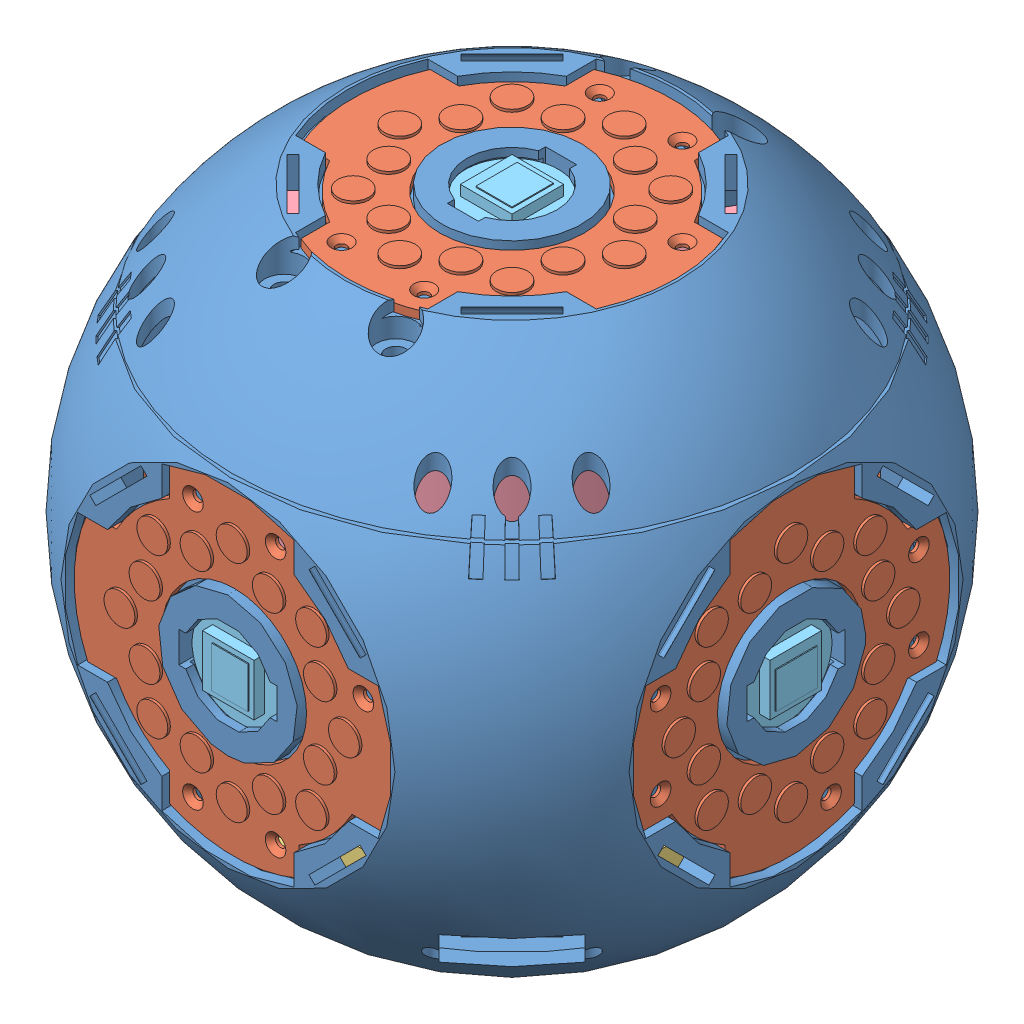
SolidWorks assembly Structural Module, configuration Passive Cube. Lengths in mm.
Overall size (63.8 63.8 63.8).
16 component instances, 5 part files, 41 mates.
Components (placement in the parent):
- Cube Shell-1: Cube Shell [Shell for Passive Cube (Large Part)] at origin size (63.8 63.8 63.8)
- Cube Shell-2: Cube Shell [Shell (Small Part)] at (0 -0.0475 0) size (55 59.4 55)
- Face Boards v2-1: Face Boards v2 [Default] at (0 0 26.1) x (1 0 0) z (0 -1 0) size (31 1.04 31)
- Face Boards v2-2: Face Boards v2 [Default] at (26.1 0 0) x (0 -1 0) z (0 0 1) size (31 1.04 31)
- Face Boards v2-3: Face Boards v2 [Default] at (0 0 -26.1) x (1 0 0) z (0 1 0) size (31 1.04 31)
- Face Boards v2-4: Face Boards v2 [Default] at (-26.1 0 0) x (0 1 0) z (0 0 1) size (31 1.04 31)
- Face Boards v2-5: Face Boards v2 [Default] at (0 -26.1 0) x (-1 0 0) z (0 0 1) size (31 1.04 31)
- Face Boards v2-6: Face Boards v2 [Default] at (0 26.0525 0) size (31 1.04 31)
- Controller PCB-1: Controller PCB [Default] at (0 -20.2874 0) x (-1 0 0) z (0 0 -1) size (43.18 6.79 43.18)
- Structural Module Internals-1: Structural Module Internals [ElectricImp] at (0 -6.4375 0) x (0 0 1) z (-1 0 0) size (49 29.1 49)
- AdjacencySensor-1: AdjacencySensor [Default] at (0 -24.9 0) x (-0.837169 0 -0.546944) z (-0.546944 0 0.837169) size (9 2.67 9)
- AdjacencySensor-2: AdjacencySensor [Default] at (24.9 0 0) x (0 -1 0) z (0 0 1) size (9 2.67 9)
- AdjacencySensor-3: AdjacencySensor [Default] at (0 0 -24.9) x (1 0 0) z (0 1 0) size (9 2.67 9)
- AdjacencySensor-4: AdjacencySensor [Default] at (0 0 24.9) x (1 0 0) z (0 -1 0) size (9 2.67 9)
- AdjacencySensor-5: AdjacencySensor [Default] at (0 24.8525 0) size (9 2.67 9)
- AdjacencySensor-6: AdjacencySensor [Default] at (-24.9 0 0) x (0 1 0) z (0 0 1) size (9 2.67 9)
Mates (geometry in assembly coordinates):
- Concentric1: concentric aligned: cylinder of Cube Shell-2 through (0 25.3525 0) axis (0 -1 0) radius 6.75; cylinder of Face Boards v2-6 through (0 26.8399 0) axis (0 -1 0) radius 7
- Coincident1: coincident anti-aligned: plane of Cube Shell-2 through (0 26.0525 0) normal (0 1 0); plane of Face Boards v2-6 through (0 26.0525 0) normal (0 -1 0)
- Parallel1: parallel aligned: line of Cube Shell-2 through (-6.4 27.4525 11.6589) axis (0 0 1); line of Face Boards v2-6 through (-6.25 26.8399 11.399) axis (0 0 1)
- Concentric2: concentric aligned: cylinder of Cube Shell-1 through (0 0 25.4) axis (0 0 -1) radius 6.75; cylinder of Face Boards v2-1 through (0 0 26.8874) axis (0 0 -1) radius 7
- Coincident3: coincident anti-aligned: plane of Cube Shell-1 through (0 0 26.1) normal (0 0 1); plane of Face Boards v2-1 through (0 0 26.1) normal (0 0 -1)
- Parallel2: parallel aligned: line of Cube Shell-1 through (-11.6589 6.4 27.5) axis (-1 0 0); line of Face Boards v2-1 through (-11.399 6.25 26.8874) axis (-1 0 0)
- Concentric3: concentric aligned: cylinder of Cube Shell-1 through (25.4 0 0) axis (-1 0 0) radius 6.75; cylinder of Face Boards v2-2 through (26.8874 0 0) axis (-1 0 0) radius 7
- Coincident5: coincident anti-aligned: plane of Cube Shell-1 through (26.1 0 0) normal (1 0 0); plane of Face Boards v2-2 through (26.1 0 0) normal (-1 0 0)
- Parallel3: parallel aligned: line of Cube Shell-1 through (27.5 6.4 -14.5465) axis (0 0 1); line of Face Boards v2-2 through (26.8874 6.25 -14.1841) axis (0 0 1)
- Concentric4: concentric aligned: cylinder of Cube Shell-1 through (-25.4 0 0) axis (1 0 0) radius 6.75; cylinder of Face Boards v2-4 through (-26.8874 0 0) axis (1 0 0) radius 7
- Parallel4: parallel aligned: line of Cube Shell-1 through (-27.5 14.5465 -6.4) axis (0 -1 0); line of Face Boards v2-4 through (-26.8874 14.1841 -6.25) axis (0 -1 0)
- Concentric5: concentric aligned: cylinder of Cube Shell-1 through (0 -25.4 0) axis (0 1 0) radius 6.75; cylinder of Face Boards v2-5 through (0 -26.8874 0) axis (0 1 0) radius 7
- Coincident9: coincident anti-aligned: plane of Cube Shell-1 through (0 -26.1 0) normal (0 -1 0); plane of Face Boards v2-5 through (0 -26.1 0) normal (0 1 0)
- Parallel5: parallel anti-aligned: line of Cube Shell-1 through (-14.5465 -27.5 6.4) axis (1 0 0); line of Face Boards v2-5 through (-11.399 -26.8874 6.25) axis (-1 0 0)
- Concentric6: concentric aligned: cylinder of Cube Shell-1 through (0 0 -25.4) axis (0 0 1) radius 6.75; cylinder of Face Boards v2-3 through (0 0 -26.8874) axis (0 0 1) radius 7
- Coincident11: coincident anti-aligned: plane of Cube Shell-1 through (0 0 -26.1) normal (0 0 -1); plane of Face Boards v2-3 through (0 0 -26.1) normal (0 0 1)
- Parallel6: parallel aligned: line of Cube Shell-1 through (14.5465 -6.4 -27.5) axis (-1 0 0); line of Face Boards v2-3 through (14.1841 -6.25 -26.8874) axis (-1 0 0)
- Coincident12: coincident anti-aligned: plane of Cube Shell-1 through (0 -6.4375 0) normal (0 1 0); plane of Structural Module Internals-1 through (0 -6.4375 0) normal (0 -1 0)
- Concentric7: concentric anti-aligned: cylinder of Structural Module Internals-1 through (13.4325 -3.0375 -21.0848) axis (0 -1 0) radius 1; cylinder of Cube Shell-1 through (13.4325 -31.9 -21.0848) axis (0 1 0) radius 0.8
- Concentric8: concentric anti-aligned: cylinder of Cube Shell-1 through (-13.4325 -31.9 -21.0848) axis (0 1 0) radius 0.8; cylinder of Structural Module Internals-1 through (-13.4325 -3.0375 -21.0848) axis (0 -1 0) radius 1
- Coincident13: coincident anti-aligned: plane of Cube Shell-2 through (0 22.6625 0) normal (0 -1 0); plane of Structural Module Internals-1 through (0 22.6625 0) normal (0 1 0)
- Concentric9: concentric anti-aligned: cylinder of Cube Shell-2 through (5.4078 27.4525 -16.6435) axis (0 -1 0) radius 1; cylinder of Structural Module Internals-1 through (5.4078 -6.4375 -16.6435) axis (0 1 0) radius 0.8
- Concentric10: concentric anti-aligned: cylinder of Cube Shell-2 through (-5.4078 27.4525 -16.6435) axis (0 -1 0) radius 1; cylinder of Structural Module Internals-1 through (-5.4078 -6.4375 -16.6435) axis (0 1 0) radius 0.8
- Concentric11: concentric anti-aligned: circle of Cube Shell-1; circle of Controller PCB-1
- Coincident15: coincident aligned: plane of Cube Shell-1 through (0 0 0) normal (0 0 1); plane of assembly through (0 0 0) normal (0 0 1)
- Coincident16: coincident aligned: plane of Cube Shell-1 through (0 0 0) normal (1 0 0); plane of assembly through (0 0 0) normal (1 0 0)
- Coincident17: coincident aligned: plane of Cube Shell-1 through (0 0 0) normal (0 1 0); plane of assembly through (0 0 0) normal (0 1 0)
- Coincident18: coincident anti-aligned: circle of Cube Shell-1; plane of Controller PCB-1 through (0 -19.5 0) normal (0 1 0)
- Parallel7: parallel anti-aligned: plane of Cube Shell-1 through (23.9645 -16.5 31.0355) normal (0.707107 0 -0.707107); plane of Controller PCB-1 through (8.0309 -16.5 14.1121) normal (-0.707107 0 0.707107)
- Coincident22: coincident anti-aligned: plane of Cube Shell-2 through (0 24.8525 0) normal (0 1 0); plane of AdjacencySensor-5 through (0 24.8525 0) normal (0 -1 0)
- Coincident24: coincident anti-aligned: plane of Cube Shell-1 through (0 -24.9 0) normal (0 -1 0); plane of AdjacencySensor-1 through (0 -24.9 0) normal (0 1 0)
- Concentric12: concentric aligned: cylinder of Cube Shell-1 through (0 -26.7 0) axis (0 1 0) radius 4.75; cylinder of AdjacencySensor-1 through (0 -26.4748 0) axis (0 1 0) radius 4.5
- Concentric13: concentric aligned: cylinder of Cube Shell-2 through (0 26.6525 0) axis (0 -1 0) radius 4.75; cylinder of AdjacencySensor-5 through (0 26.4273 0) axis (0 -1 0) radius 4.5
- Coincident26: coincident anti-aligned: plane of Cube Shell-1 through (0 0 24.9) normal (0 0 1); plane of AdjacencySensor-4 through (0 0 24.9) normal (0 0 -1)
- Coincident27: coincident anti-aligned: plane of Cube Shell-1 through (24.9 0 0) normal (1 0 0); plane of AdjacencySensor-2 through (24.9 0 0) normal (-1 0 0)
- Concentric14: concentric aligned: cylinder of Cube Shell-1 through (26.7 0 0) axis (-1 0 0) radius 4.75; cylinder of AdjacencySensor-2 through (26.4748 0 0) axis (-1 0 0) radius 4.5
- Concentric15: concentric aligned: cylinder of Cube Shell-1 through (0 0 26.7) axis (0 0 -1) radius 4.75; cylinder of AdjacencySensor-4 through (0 0 26.4748) axis (0 0 -1) radius 4.5
- Coincident28: coincident anti-aligned: plane of Cube Shell-1 through (-24.9 0 0) normal (-1 0 0); plane of AdjacencySensor-6 through (-24.9 0 0) normal (1 0 0)
- Concentric16: concentric aligned: cylinder of Cube Shell-1 through (-26.7 0 0) axis (1 0 0) radius 4.75; cylinder of AdjacencySensor-6 through (-26.4748 0 0) axis (1 0 0) radius 4.5
- Coincident29: coincident anti-aligned: plane of Cube Shell-1 through (0 0 -24.9) normal (0 0 -1); plane of AdjacencySensor-3 through (0 0 -24.9) normal (0 0 1)
- Concentric17: concentric aligned: cylinder of Cube Shell-1 through (0 0 -26.7) axis (0 0 1) radius 4.75; cylinder of AdjacencySensor-3 through (0 0 -26.4748) axis (0 0 1) radius 4.5
